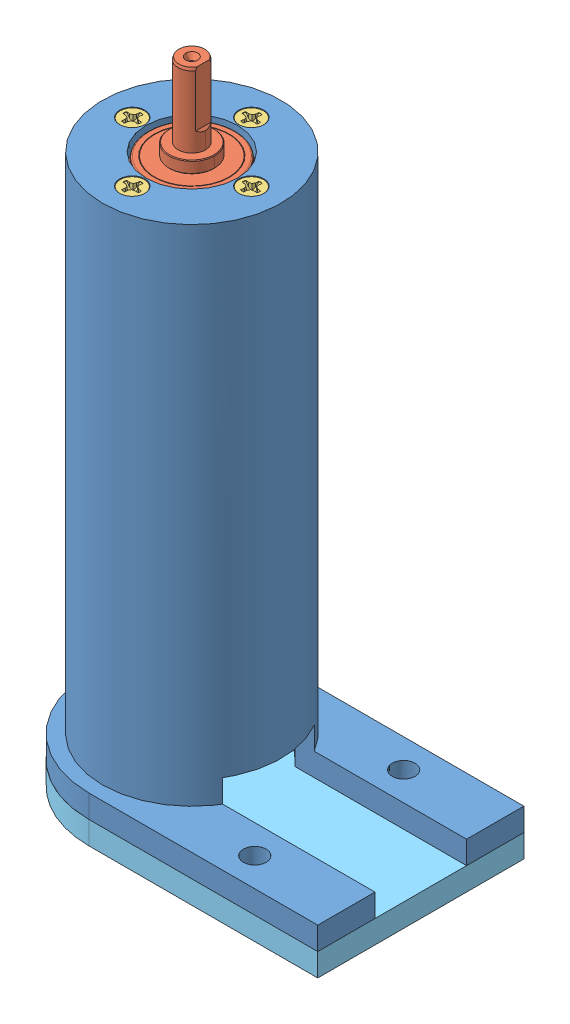
SolidWorks assembly Motor2Column, configuration Default. Lengths in mm.
Overall size (72.5 138 45).
8 component instances, 5 part files, 8 mates.
Components (placement in the parent):
- MotorSleeve-1: MotorSleeve [Default] at (-37.0074 70.7505 8.7805) size (72.5 115 45)
- 166158_GP32A-2st.stp-2: 166158_GP32A-2st.stp [Default] at (-37.0074 67.7505 8.7805) x (0 -1 0) z (0 0 1) size (57.4 32 32)
- 90382A262_Phillips Thread-Locking Flat Head Screws-1: 90382A262_Phillips Thread-Locking Flat Head Screws [90382A262] at (-24.0074 69.0114 8.7805) x (0.993754 0 0.111596) z (0 1 0) size (5.6 5.6 8.19)
- 90382A262_Phillips Thread-Locking Flat Head Screws-2: 90382A262_Phillips Thread-Locking Flat Head Screws [90382A262] at (-37.0074 69.0114 -4.2195) x (0.111596 0 -0.993754) z (0 1 0) size (5.6 5.6 8.19)
- 90382A262_Phillips Thread-Locking Flat Head Screws-3: 90382A262_Phillips Thread-Locking Flat Head Screws [90382A262] at (-50.0074 69.0114 8.7805) x (-0.993754 0 -0.111596) z (0 1 0) size (5.6 5.6 8.19)
- 90382A262_Phillips Thread-Locking Flat Head Screws-4: 90382A262_Phillips Thread-Locking Flat Head Screws [90382A262] at (-37.0074 69.0114 21.7805) x (-0.111596 0 0.993754) z (0 1 0) size (5.6 5.6 8.19)
- 268193_RE30_GB_60W_KL_2WE.stp-1: 268193_RE30_GB_60W_KL_2WE.stp [Default] at (-37.0074 36.0355 8.7805) x (0 -1 0) z (0 0 1) size (96.7 30 30)
- ColumnCap-1: ColumnCap [Default] at (-37.0074 -49.2495 8.7805) size (72.5 5 45)
Mates (geometry in assembly coordinates):
- Gearbox and Sleeve: concentric aligned: circle of MotorSleeve-1; circle of 166158_GP32A-2st.stp-2
- Screwholes of Gear and Sleeve: concentric anti-aligned: circle of MotorSleeve-1; circle of 166158_GP32A-2st.stp-2
- Screws: concentric anti-aligned: cone of 166158_GP32A-2st.stp-2; cone of 90382A262_Phillips Thread-Locking Flat Head Screws-1 through (-24.0074 70.6614 8.7805) axis (0 -1 0)
- Coincident3: coincident anti-aligned: plane of MotorSleeve-1 through (-37.0074 67.7505 8.7805) normal (0 -1 0); plane of 166158_GP32A-2st.stp-2 through (-37.0074 67.7505 8.7805) normal (0 1 0)
- Concentric5: concentric aligned: circle of 166158_GP32A-2st.stp-2; circle of 268193_RE30_GB_60W_KL_2WE.stp-1
- M+G Alignment: concentric aligned: cylinder of 166158_GP32A-2st.stp-2 through (-37.0074 33.1505 -4.5945) axis (0 0 -1) radius 1.025; cylinder of 268193_RE30_GB_60W_KL_2WE.stp-1 through (-37.0074 33.1505 0.3518) axis (0 0 -1) radius 1
- Concentric6: concentric aligned: circle of MotorSleeve-1; circle of ColumnCap-1
- Coincident4: coincident anti-aligned: plane of MotorSleeve-1 through (-37.0074 -44.2495 8.7805) normal (0 -1 0); plane of ColumnCap-1 through (-37.0074 -44.2495 8.7805) normal (0 1 0)
